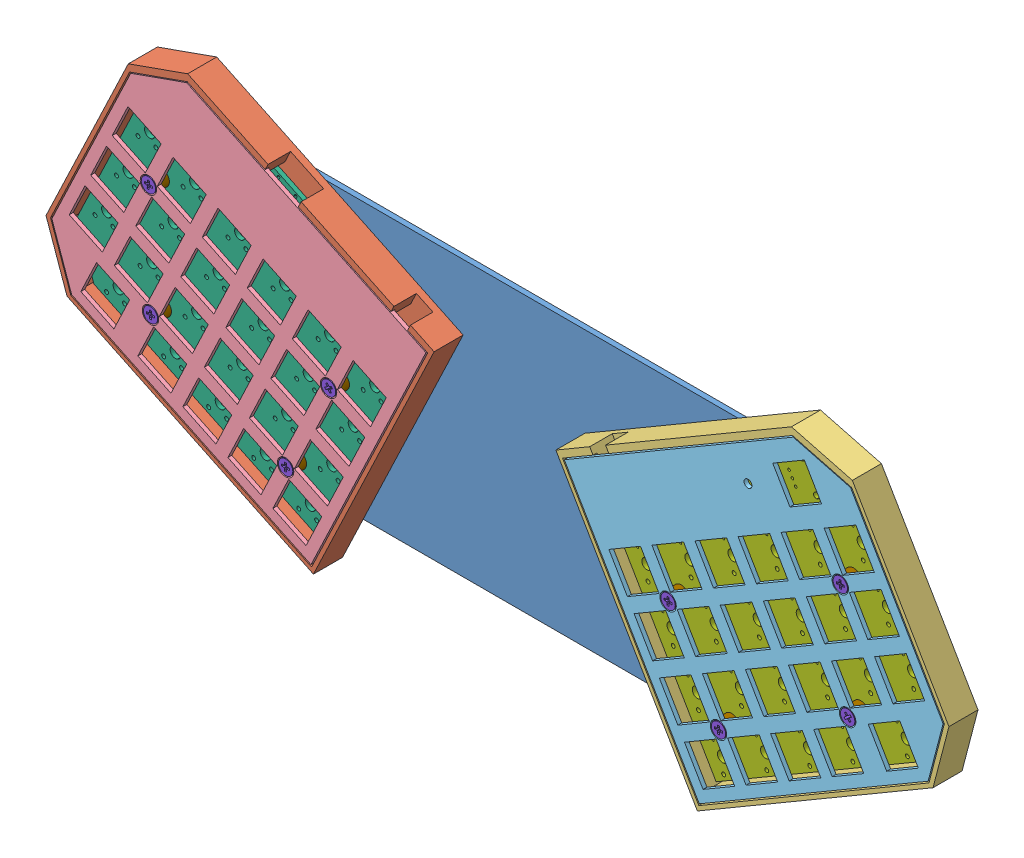
SolidWorks assembly Assemblage, configuration Défaut. Lengths in mm.
Overall size (360.69 153.79 13.1).
23 component instances, 9 part files, 38 mates.
Components (placement in the parent):
- support-1: support [Défaut] at (-120.9663 42.2861 204.9075) size (236 105 2)
- left back-1: left back [Défaut] at (-136.6414 64.9835 206.9075) x (0.902585 -0.430511 0) z (0 0 1) size (121.25 107 11.1)
- right back-1: right back [Défaut] at (177.6144 -18.7238 206.9075) x (-0.862989 -0.505223 0) z (0 0 1) size (121.25 107 11.1)
- left plate-1: left plate [Défaut] at (-134.4035 65.0296 216.5075) x (0.902585 -0.430511 0) z (0 0 1) size (117.25 102 1.5)
- right plate-1: right plate [Défaut] at (126.3783 64.8455 218.0075) x (-0.862989 -0.505223 0) z (0 0 -1) size (117.25 102 1.5)
- left pcb-1: left pcb [Défaut] at (-120.731 122.7181 211.4075) x (0.902585 -0.430511 0) z (0 0 1) size (109.22 95.25 1.6)
- right pcb-1: right pcb [Défaut] at (-112.962 -8.1164 211.4075) x (0.862989 0.505223 0) z (0 0 1) size (109.22 95.25 1.6)
- screw-41: screw [ISO 7046-1 - M3 x 4 - Z - 4N] at (83.5636 -53.4713 218.0075) x (0 0 -1) z (0.99991 -0.013393 0) size (11 5.5 5.5)
- screw-42: screw [ISO 7046-1 - M3 x 4 - Z - 4N] at (64.3146 -20.5914 218.0075) x (0 0 -1) z (0.999445 -0.0333 0) size (11 5.5 5.5)
- screw-37: screw [ISO 7046-1 - M3 x 4 - Z - 4N] at (132.8834 -24.5978 218.0075) x (0 0 -1) z (0.638299 -0.769788 0) size (11 5.5 5.5)
- screw-36: screw [ISO 7046-1 - M3 x 4 - Z - 4N] at (130.0743 17.9066 218.0075) x (0 0 -1) z (-0.080367 0.996765 0) size (11 5.5 5.5)
- screw-43: screw [ISO 7046-1 - M3 x 4 - Z - 4N] at (-134.1209 17.9463 218.0075) x (0 0 -1) z (0.997216 -0.074568 0) size (11 5.5 5.5)
- screw-38: screw [ISO 7046-1 - M3 x 4 - Z - 4N] at (-65.3439 -14.8587 218.0075) x (0 0 -1) z (-0.508564 0.861024 0) size (11 5.5 5.5)
- screw-44: screw [ISO 7046-1 - M3 x 4 - Z - 4N] at (-81.7463 -49.2472 218.0075) x (0 0 -1) z (0.999796 -0.020219 0) size (11 5.5 5.5)
- screw-40: screw [ISO 7046-1 - M3 x 4 - Z - 4N] at (-133.3291 -24.6435 218.0075) x (0 0 -1) z (0.999987 0.005191 0) size (11 5.5 5.5)
- spacer-3: spacer [Défaut] at (64.3146 -20.5914 216.5075) x (1 0 0) z (0 1 0) size (6 3.5 6)
- spacer-4: spacer [Défaut] at (132.8834 -24.5978 216.5075) x (1 0 0) z (0 1 0) size (6 3.5 6)
- spacer-5: spacer [Défaut] at (83.5636 -53.4713 216.5075) x (1 0 0) z (0 1 0) size (6 3.5 6)
- spacer-6: spacer [Défaut] at (130.0743 17.9066 216.5075) x (0.999981 0.006129 0) z (-0.006129 0.999981 0) size (6 3.5 6)
- spacer-7: spacer [Défaut] at (-133.3291 -24.6435 216.5075) x (1 0 0) z (0 1 0) size (6 3.5 6)
- spacer-8: spacer [Défaut] at (-81.7463 -49.2472 216.5075) x (1 0 0) z (0 1 0) size (6 3.5 6)
- spacer-9: spacer [Défaut] at (-134.1209 17.9463 216.5075) x (1 0 0) z (0 1 0) size (6 3.5 6)
- spacer-10: spacer [Défaut] at (-65.3439 -14.8587 216.5075) x (1 0 0) z (0 1 0) size (6 3.5 6)
Mates (geometry in assembly coordinates):
- Coïncidente1: coincident anti-aligned: plane of support-1 through (-120.9663 42.2861 206.9075) normal (0 0 1); plane of right back-1 through (72.7245 -164.8046 206.9423) normal (0 0 -1)
- Coïncidente2: coincident anti-aligned: plane of support-1 through (-120.9663 42.2861 206.9075) normal (0 0 1); plane of left back-1 through (-136.6414 64.9835 206.9075) normal (0 0 -1)
- Coïncidente12: coincident aligned: cone of right plate-1 through (83.5636 -53.4713 218.0075) axis (0 0 -1); cone of screw-41 through (83.5636 -53.4713 217.6075) axis (0 0 -1)
- Coïncidente13: coincident aligned: cone of right plate-1 through (64.3146 -20.5914 218.0075) axis (0 0 -1); cone of screw-42 through (64.3146 -20.5914 217.6075) axis (0 0 -1)
- Coïncidente14: coincident aligned: cone of right plate-1 through (132.8834 -24.5978 218.0075) axis (0 0 -1); cone of screw-37 through (132.8834 -24.5978 217.6075) axis (0 0 -1)
- Coïncidente15: coincident aligned: cone of right plate-1 through (130.0743 17.9066 218.0075) axis (0 0 -1); cone of screw-36 through (130.0743 17.9066 217.6075) axis (0 0 -1)
- Coïncidente16: coincident aligned: cone of left plate-1 through (-134.1209 17.9463 218.0075) axis (0 0 -1); cone of screw-43 through (-134.1209 17.9463 217.6075) axis (0 0 -1)
- Coïncidente17: coincident aligned: cone of left plate-1 through (-65.3439 -14.8587 218.0075) axis (0 0 -1); cone of screw-38 through (-65.3439 -14.8587 217.6075) axis (0 0 -1)
- Coïncidente18: coincident aligned: cone of left plate-1 through (-81.7463 -49.2472 218.0075) axis (0 0 -1); cone of screw-44 through (-81.7463 -49.2472 217.6075) axis (0 0 -1)
- Coïncidente19: coincident aligned: cone of left plate-1 through (-133.3291 -24.6435 218.0075) axis (0 0 -1); cone of screw-40 through (-133.3291 -24.6435 217.6075) axis (0 0 -1)
- Coaxiale1: concentric anti-aligned: cylinder of screw-42 through (64.3146 -20.5914 224.3575) axis (0 0 1) radius 1.5; cylinder of spacer-3 through (64.3146 -20.5914 212.7279) axis (0 0 -1) radius 1.75
- Coïncidente20: coincident anti-aligned: plane of right plate-1 through (126.3783 64.8455 216.5075) normal (0 0 -1); plane of spacer-3 through (64.3146 -22.3414 216.5075) normal (0 0 1)
- Coaxiale3: concentric anti-aligned: cylinder of screw-37 through (132.8834 -24.5978 224.3575) axis (0 0 1) radius 1.5; cylinder of spacer-4 through (132.8834 -24.5978 212.7279) axis (0 0 -1) radius 1.75
- Coïncidente21: coincident anti-aligned: plane of right plate-1 through (126.3783 64.8455 216.5075) normal (0 0 -1); plane of spacer-4 through (132.8834 -26.3478 216.5075) normal (0 0 1)
- Coaxiale4: concentric anti-aligned: cylinder of screw-41 through (83.5636 -53.4713 224.3575) axis (0 0 1) radius 1.5; cylinder of spacer-5 through (83.5636 -53.4713 212.7279) axis (0 0 -1) radius 1.75
- Coïncidente22: coincident anti-aligned: plane of right plate-1 through (126.3783 64.8455 216.5075) normal (0 0 -1); plane of spacer-5 through (83.5636 -55.2213 216.5075) normal (0 0 1)
- Coaxiale5: concentric anti-aligned: cylinder of screw-36 through (130.0743 17.9066 224.3575) axis (0 0 1) radius 1.5; cylinder of spacer-6 through (130.0743 17.9066 212.7279) axis (0 0 -1) radius 1.75
- Coïncidente23: coincident aligned: plane of right plate-1 through (126.3783 64.8455 216.5075) normal (0 0 -1); circle of spacer-6
- Coaxiale6: concentric anti-aligned: cylinder of screw-38 through (-65.3439 -14.8587 224.3575) axis (0 0 1) radius 1.5; cylinder of spacer-10 through (-65.3439 -14.8587 212.7279) axis (0 0 -1) radius 1.75
- Coaxiale7: concentric anti-aligned: cylinder of screw-44 through (-81.7463 -49.2472 224.3575) axis (0 0 1) radius 1.5; circle of spacer-8
- Coaxiale8: concentric anti-aligned: cylinder of screw-40 through (-133.3291 -24.6435 224.3575) axis (0 0 1) radius 1.5; circle of spacer-7
- Coaxiale9: concentric anti-aligned: cylinder of screw-43 through (-134.1209 17.9463 224.3575) axis (0 0 1) radius 1.5; cylinder of spacer-9 through (-134.1209 17.9463 212.7279) axis (0 0 -1) radius 1.75
- Coïncidente24: coincident anti-aligned: plane of left plate-1 through (-134.4035 65.0296 216.5075) normal (0 0 -1); plane of spacer-8 through (-81.7463 -50.9972 216.5075) normal (0 0 1)
- Coïncidente25: coincident anti-aligned: plane of left plate-1 through (-134.4035 65.0296 216.5075) normal (0 0 -1); plane of spacer-10 through (-65.3439 -16.6087 216.5075) normal (0 0 1)
- Coïncidente26: coincident anti-aligned: plane of left plate-1 through (-134.4035 65.0296 216.5075) normal (0 0 -1); plane of spacer-7 through (-133.3291 -26.3935 216.5075) normal (0 0 1)
- Coïncidente27: coincident anti-aligned: plane of left plate-1 through (-134.4035 65.0296 216.5075) normal (0 0 -1); plane of spacer-9 through (-134.1209 16.1963 216.5075) normal (0 0 1)
- Coaxiale10: concentric aligned: cylinder of left pcb-1 through (-134.1209 17.9463 210.6075) axis (0 0 1) radius 2.25; cylinder of screw-43 through (-134.1209 17.9463 224.3575) axis (0 0 1) radius 1.5
- Coaxiale11: concentric aligned: cylinder of left pcb-1 through (-65.3439 -14.8587 210.6075) axis (0 0 1) radius 2.25; cylinder of screw-38 through (-65.3439 -14.8587 224.3575) axis (0 0 1) radius 1.5
- Coïncidente30: coincident anti-aligned: plane of left back-1 through (-63.0837 -10.1201 211.4075) normal (0 0 1); plane of left pcb-1 through (-52.116 -27.7649 211.4075) normal (0 0 -1)
- Coïncidente31: coincident: plane of left plate-1 through (-134.4035 65.0296 216.5075) normal (0 0 -1); line of left back-1 through (-31.7158 14.9366 216.5075) axis (-0.430511 -0.902585 0)
- Coaxiale13: concentric anti-aligned: cylinder of left back-1 through (-65.3439 -14.8587 209.4075) axis (0 0 -1) radius 1.75; cylinder of screw-38 through (-65.3439 -14.8587 224.3575) axis (0 0 1) radius 1.5
- Coaxiale14: concentric anti-aligned: cylinder of left back-1 through (-81.7463 -49.2472 209.4075) axis (0 0 -1) radius 1.75; cylinder of screw-44 through (-81.7463 -49.2472 224.3575) axis (0 0 1) radius 1.5
- Coaxiale15: concentric aligned: cylinder of right pcb-1 through (64.3146 -20.5914 210.6075) axis (0 0 1) radius 2.25; cylinder of screw-42 through (64.3146 -20.5914 224.3575) axis (0 0 1) radius 1.5
- Coaxiale16: concentric aligned: cylinder of right pcb-1 through (130.0743 17.9066 210.6075) axis (0 0 1) radius 2.25; cylinder of screw-36 through (130.0743 17.9066 224.3575) axis (0 0 1) radius 1.5
- Coïncidente34: coincident: line of right back-1 through (77.292 -77.456 216.5075) axis (-0.505223 0.862989 0); plane of right plate-1 through (126.3783 64.8455 216.5075) normal (0 0 -1)
- Coïncidente35: coincident anti-aligned: plane of right back-1 through (23.4628 -173.331 211.4423) normal (0 0 1); plane of right pcb-1 through (50.0894 -35.8188 211.4075) normal (0 0 -1)
- Coaxiale19: concentric anti-aligned: cylinder of right back-1 through (25.1845 -128.1742 209.4423) axis (0 0 -1) radius 1.75; cylinder of screw-36 through (130.0743 17.9066 224.3575) axis (0 0 1) radius 1.5
- Coaxiale20: concentric anti-aligned: cylinder of right back-1 through (-40.5753 -166.6722 209.4423) axis (0 0 -1) radius 1.75; cylinder of screw-42 through (64.3146 -20.5914 224.3575) axis (0 0 1) radius 1.5
